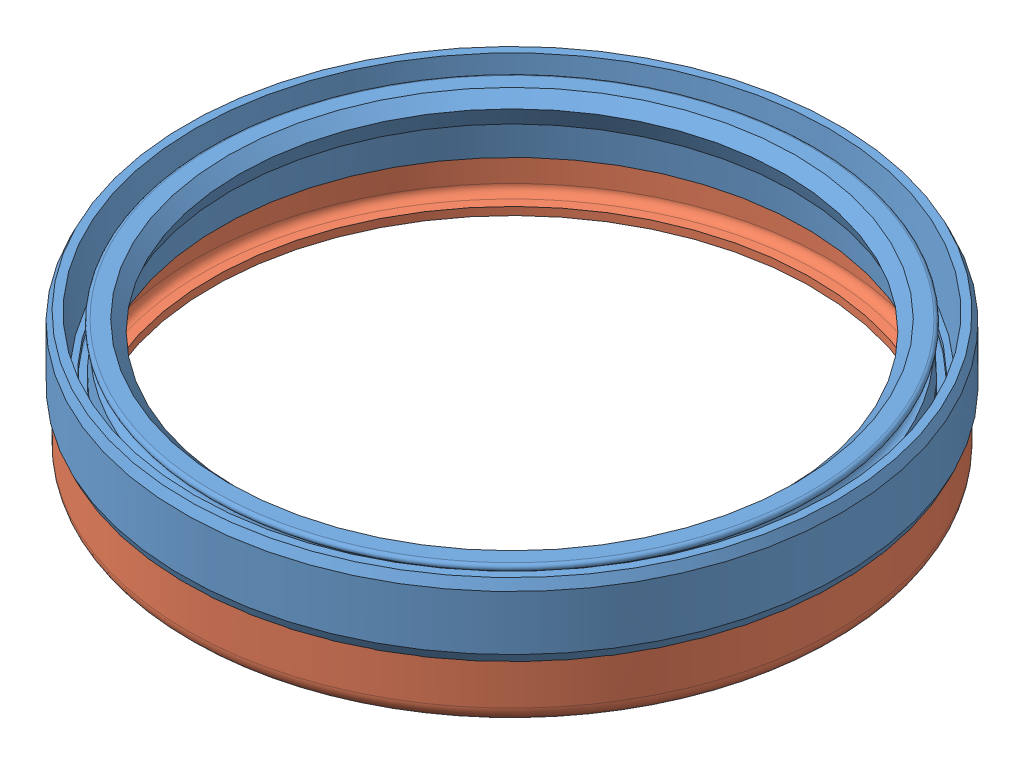
SolidWorks assembly b90x110x12_gb9877_1_1, configuration 默认. Lengths in mm.
Overall size (148.38 21.23 148.38).
2 component instances, 2 part files, 0 mates.
Components (placement in the parent):
- b90x110x12_gb9877_1_rubber_1-1: b90x110x12_gb9877_1_rubber_1 [默认] at (13.055 -6.8163 -14.7108) size (108.6 12 108.6)
- b90x110x12_gb9877_1_frame_1-1: b90x110x12_gb9877_1_frame_1 [默认] at (13.055 -22.0467 -14.7108) x (-0.837169 0 -0.546944) z (0.546944 0 -0.837169) size (107.2 9.5 107.2)
